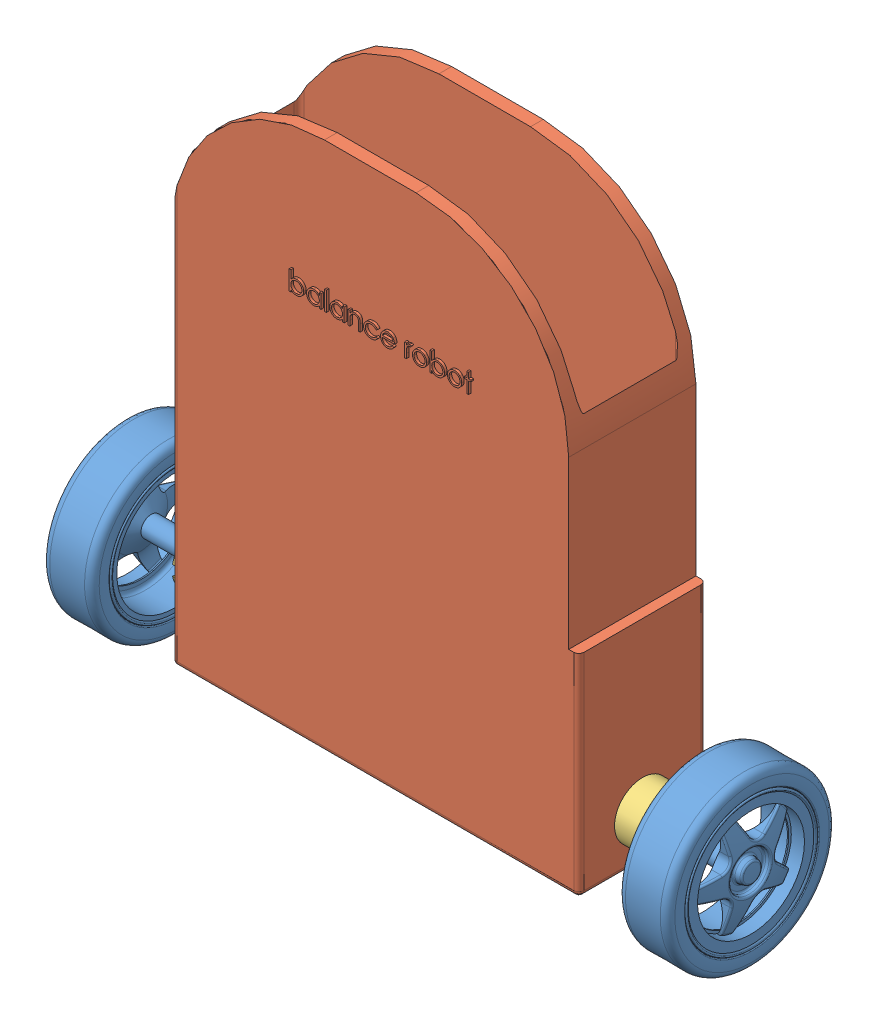
SolidWorks assembly Assem2, configuration Varsayılan. Lengths in mm.
Overall size (246.25 236.79 92.58).
6 component instances, 4 part files, 13 mates.
Components (placement in the parent):
- Rueda 01-1: Rueda 01 [Predeterminado] at (-6.0168 -6.6593 65.4141) x (1 0 0) z (0 0.79145 0.611234) size (25 66 66)
- Rueda 01-2: Rueda 01 [Predeterminado] at (-212.2668 -6.6593 65.4141) x (-1 0 0) z (0 0.818721 -0.574191) size (25 66 66)
- Part1-1: Part1 [Varsayılan] at (-109.1668 -19.6593 65.4141) size (160 208.5 51)
- Robotzone Gearmotor 195RPM - 12VDC - ServoCity #638256-1: Robotzone Gearmotor 195RPM - 12VDC - ServoCity #638256 [Default] at (-19.1168 -6.6593 65.4141) x (0 -0.916838 -0.39926) z (0 -0.39926 0.916838) size (22 69.3 22)
- Robotzone Gearmotor 195RPM - 12VDC - ServoCity #638256-2: Robotzone Gearmotor 195RPM - 12VDC - ServoCity #638256 [Default] at (-199.1668 -6.6593 65.4141) x (0 1 0) z (0 0 1) size (22 69.3 22)
- ArduinoMega-1: ArduinoMega [Default] at (-106.9731 67.1451 47.0651) x (-1 0 0) z (0 0 -1) size (107.95 53.42 12.95)
Mates (geometry in assembly coordinates):
- Eş Merkezli1: concentric aligned: cylinder of Part1-1 through (-277.1668 -6.6593 65.4141) axis (1 0 0) radius 11; cylinder of Robotzone Gearmotor 195RPM - 12VDC - ServoCity #638256-1 through (-64.6168 -6.6593 65.4141) axis (1 0 0) radius 10.825
- Çakışık2: coincident aligned: circle of Part1-1; circle of Robotzone Gearmotor 195RPM - 12VDC - ServoCity #638256-1
- Eş Merkezli3: concentric anti-aligned: cylinder of Part1-1 through (-277.1668 -6.6593 65.4141) axis (1 0 0) radius 11; cylinder of Robotzone Gearmotor 195RPM - 12VDC - ServoCity #638256-2 through (-153.6668 -6.6593 65.4141) axis (-1 0 0) radius 10.825
- Çakışık4: coincident aligned: circle of Part1-1; circle of Robotzone Gearmotor 195RPM - 12VDC - ServoCity #638256-2
- Eş Merkezli4: concentric anti-aligned: cylinder of Rueda 01-1 through (1.4012 -6.6593 65.4141) axis (1 0 0) radius 4; cylinder of Robotzone Gearmotor 195RPM - 12VDC - ServoCity #638256-1 through (-1.0168 -6.6593 65.4141) axis (-1 0 0) radius 2
- Çakışık5: coincident anti-aligned: plane of Rueda 01-1 through (-1.0168 -6.6593 65.4141) normal (-1 0 0); plane of Robotzone Gearmotor 195RPM - 12VDC - ServoCity #638256-1 through (-1.0168 -6.6593 65.4141) normal (1 0 0)
- Eş Merkezli5: concentric anti-aligned: cylinder of Rueda 01-2 through (-219.6848 -6.6593 65.4141) axis (-1 0 0) radius 4; cylinder of Robotzone Gearmotor 195RPM - 12VDC - ServoCity #638256-2 through (-217.2668 -6.6593 65.4141) axis (1 0 0) radius 2
- Çakışık6: coincident anti-aligned: plane of Rueda 01-2 through (-217.2668 -6.6593 65.4141) normal (1 0 0); plane of Robotzone Gearmotor 195RPM - 12VDC - ServoCity #638256-2 through (-217.2668 -6.6593 65.4141) normal (-1 0 0)
- Kilitle1: lock: unknown of Part1-1; unknown of Robotzone Gearmotor 195RPM - 12VDC - ServoCity #638256-1
- Kilitle2: lock: unknown of Part1-1; unknown of Robotzone Gearmotor 195RPM - 12VDC - ServoCity #638256-2
- Çakışık10: coincident anti-aligned: plane of Part1-1 through (-184.1668 240.3407 45.4141) normal (0 0 1); plane of ArduinoMega-1 through (-157.7731 40.437 45.4141) normal (0 0 -1)
- Paralel2: parallel anti-aligned: plane of Part1-1 through (-182.1668 40.3407 47.4141) normal (0 1 0); plane of ArduinoMega-1 through (-56.1731 40.437 45.4141) normal (0 -1 0)
- Kilitle3: lock: unknown of Part1-1; unknown of ArduinoMega-1
